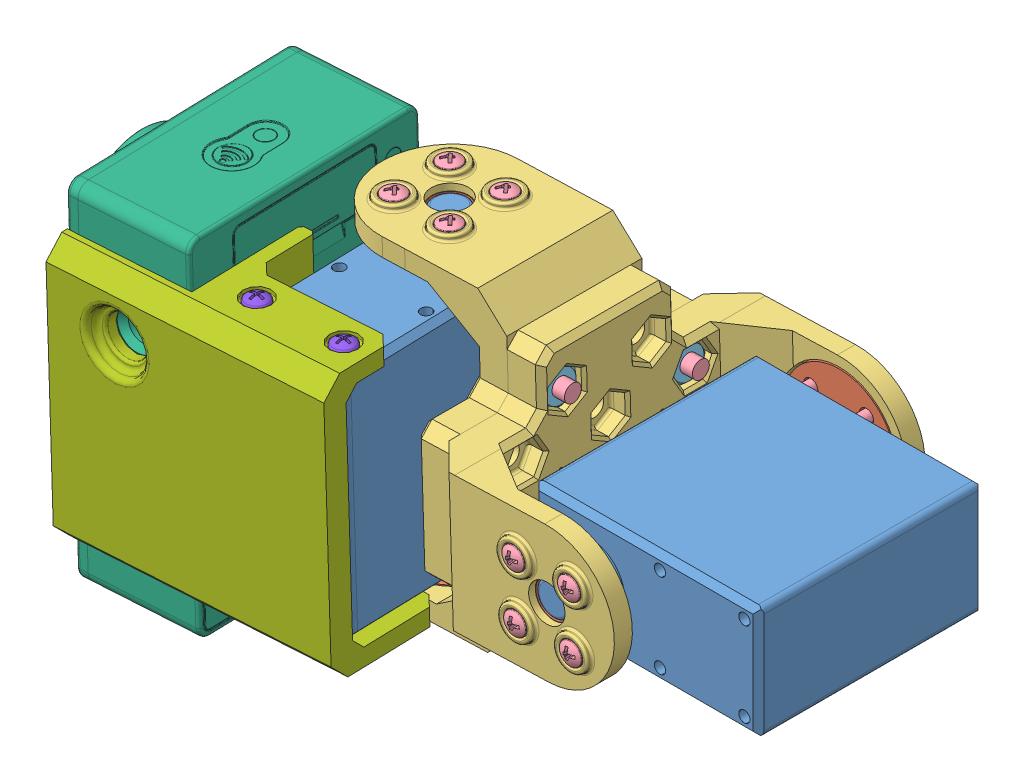
SolidWorks assembly Gimbal, configuration По умолчанию. Lengths in mm.
Overall size (118.51 61.53 66.21).
45 component instances, 8 part files, 20 mates.
Components (placement in the parent):
- Coxa-1: Coxa [По умолчанию] at origin size (86.89 58.77 58.33) (flexible)
  - Servo-1: Servo [По умолчанию] at origin size (40.32 20.63 52.9) (flexible)
    - RDS3115MG-1: RDS3115MG [00] at origin size (40 20 52)
    - Disk_25T-1: Disk_25T [Servo_Disk_T25] at (-10 0 44.4) x (0.032098 -0.999485 0) z (-0.999485 -0.032098 0) size (20 2 20)
    - Disk_25T-2: Disk_25T [Disk_T25] at (-10 0 -6.4) x (0.032098 -0.999485 0) z (-0.999485 -0.032098 0) size (20 4.5 20)
  - FemurPart4-3: FemurPart4 [По умолчанию] at (-10 0 -7.6) x (0.032098 -0.999485 0) z (0 0 1) size (45.2 34 57.2)
  - FemurPart4-4: FemurPart4 [По умолчанию] at (-54.8632 26.1734 19.9999) x (0 0 1) z (0.032098 -0.999485 0) size (45.2 34 57.2)
  - pan head cross recess screw_iso-1: pan head cross recess screw_iso [ISO 7045 - M2 x 5 - Z --- 5S] at (-59.8618 27.6137 15.0502) x (0.032098 -0.999485 0) z (-0.73565 -0.023625 0.67695) size (6.56 4 4)
  - pan head cross recess screw_iso-2: pan head cross recess screw_iso [ISO 7045 - M2 x 5 - Z --- 5S] at (-49.9674 27.9314 15.0502) x (0.032098 -0.999485 0) z (-0.73565 -0.023625 0.67695) size (6.56 4 4)
  - pan head cross recess screw_iso-3: pan head cross recess screw_iso [ISO 7045 - M2 x 5 - Z --- 5S] at (-59.8618 27.6137 24.9496) x (0.032098 -0.999485 0) z (-0.73565 -0.023625 0.67695) size (6.56 4 4)
  - pan head cross recess screw_iso-4: pan head cross recess screw_iso [ISO 7045 - M2 x 5 - Z --- 5S] at (-49.9674 27.9314 24.9496) x (0.032098 -0.999485 0) z (-0.73565 -0.023625 0.67695) size (6.56 4 4)
  - pan head cross recess screw_iso-5: pan head cross recess screw_iso [ISO 7045 - M2 x 5 - Z --- 5S] at (-48.0929 -30.4385 24.9496) x (-0.032098 0.999485 0) z (0.731511 0.023492 0.681425) size (6.56 4 4)
  - pan head cross recess screw_iso-6: pan head cross recess screw_iso [ISO 7045 - M2 x 5 - Z --- 5S] at (-57.9873 -30.7563 24.9496) x (-0.032098 0.999485 0) z (0 0 1) size (6.56 4 4)
  - pan head cross recess screw_iso-7: pan head cross recess screw_iso [ISO 7045 - M2 x 5 - Z --- 5S] at (-57.9873 -30.7563 15.0502) x (-0.032098 0.999485 0) z (0 0 1) size (6.56 4 4)
  - pan head cross recess screw_iso-8: pan head cross recess screw_iso [ISO 7045 - M2 x 5 - Z --- 5S] at (-48.0929 -30.4385 15.0502) x (-0.032098 0.999485 0) z (0 0 1) size (6.56 4 4)
  - pan head cross recess screw_iso-9: pan head cross recess screw_iso [ISO 7045 - M2 x 5 - Z --- 5S] at (-4.8939 -4.7883 49.2) x (0 0 -1) z (0.994673 0.103085 0) size (6.56 4 4)
  - pan head cross recess screw_iso-10: pan head cross recess screw_iso [ISO 7045 - M2 x 5 - Z --- 5S] at (-10 0 41.6) x (0 0 -1) z (0.994673 0.103085 0) size (6.56 4 4)
  - pan head cross recess screw_iso-11: pan head cross recess screw_iso [ISO 7045 - M2 x 5 - Z --- 5S] at (-10 0 43.6) x (0 0 -1) z (0.994673 0.103085 0) size (6.56 4 4)
  - pan head cross recess screw_iso-12: pan head cross recess screw_iso [ISO 7045 - M2 x 5 - Z --- 5S] at (-14.7883 -5.1061 49.2) x (0 0 -1) z (0.994673 0.103085 0) size (6.56 4 4)
  - pan head cross recess screw_iso-13: pan head cross recess screw_iso [ISO 7045 - M2 x 5 - Z --- 5S] at (-15.1061 4.7883 49.2) x (0 0 -1) z (0.994673 0.103085 0) size (6.56 4 4)
  - pan head cross recess screw_iso-14: pan head cross recess screw_iso [ISO 7045 - M2 x 5 - Z --- 5S] at (-5.2117 5.1061 49.2) x (0 0 -1) z (0.994673 0.103085 0) size (6.56 4 4)
  - pan head cross recess screw_iso-15: pan head cross recess screw_iso [ISO 7045 - M2 x 5 - Z --- 5S] at (-4.8939 -4.7883 -9.2) x (0 0 1) z (-0.958293 -0.285786 0) size (6.56 4 4)
  - pan head cross recess screw_iso-16: pan head cross recess screw_iso [ISO 7045 - M2 x 5 - Z --- 5S] at (-14.7883 -5.1061 -9.2) x (0 0 1) z (-0.958293 -0.285786 0) size (6.56 4 4)
  - pan head cross recess screw_iso-17: pan head cross recess screw_iso [ISO 7045 - M2 x 5 - Z --- 5S] at (-15.1061 4.7883 -9.2) x (0 0 1) z (-0.958293 -0.285786 0) size (6.56 4 4)
  - pan head cross recess screw_iso-18: pan head cross recess screw_iso [ISO 7045 - M2 x 5 - Z --- 5S] at (-5.2117 5.1061 -9.2) x (0 0 1) z (-0.958293 -0.285786 0) size (6.56 4 4)
  - pan head cross recess screw_iso-19: pan head cross recess screw_iso [ISO 7045 - M3 x 10 - Z --- 10N] at (-10 0 -8.8) x (0 0 1) z (-0.958293 -0.285786 0) size (12.35 5.6 5.6)
  - pan head cross recess screw_iso-20: pan head cross recess screw_iso [ISO 7045 - M3 x 10 - Z --- 10N] at (-37.6266 6.6165 4.9999) x (0.999485 0.032098 0) z (-0.021408 0.666616 -0.745094) size (12.35 5.6 5.6)
  - pan head cross recess screw_iso-21: pan head cross recess screw_iso [ISO 7045 - M3 x 10 - Z --- 10N] at (-37.1451 -8.3757 34.9999) x (0.999485 0.032098 0) z (0.022707 -0.707059 -0.706789) size (12.35 5.6 5.6)
  - pan head cross recess screw_iso-22: pan head cross recess screw_iso [ISO 7045 - M3 x 10 - Z --- 10N] at (-37.8674 14.1128 27.5) x (0.999485 0.032098 0) z (0.027077 -0.843132 -0.537024) size (12.35 5.6 5.6)
  - pan head cross recess screw_iso-23: pan head cross recess screw_iso [ISO 7045 - M3 x 10 - Z --- 10N] at (-36.9044 -15.8718 12.5) x (0.999485 0.032098 0) z (-0.03148 0.980231 0.195335) size (12.35 5.6 5.6)
  - nut-1: nut [00] at (-28.3314 6.9151 4.9999) x (0.032092 -0.999304 0.019008) z (-0.999485 -0.032098 0) size (5.5 6.35 1.8)
  - nut-2: nut [00] at (-28.5721 14.4113 27.5) x (0.028029 -0.872784 -0.487301) z (-0.999485 -0.032098 0) size (5.5 6.35 1.8)
  - nut-3: nut [00] at (-27.6092 -15.5732 12.5) x (0.026892 -0.837382 -0.545956) z (-0.999485 -0.032098 0) size (5.5 6.35 1.8)
  - nut-4: nut [00] at (-27.8499 -8.0772 34.9999) x (0.032 -0.996424 0.078198) z (-0.999485 -0.032098 0) size (5.5 6.35 1.8)
- Servo-1: Servo [По умолчанию] at (-53.0421 -21.3927 29.9956) x (0.029326 0.000942 0.999569) z (-0.032098 0.999485 0) size (40.29 20.58 52.9) (flexible)
  - RDS3115MG-1: RDS3115MG [00] at origin size (40 20 52)
  - Disk_25T-1: Disk_25T [Servo_Disk_T25] at (-10 0 44.4) x (-0.999569 0.029341 0) z (0.029341 0.999569 0) size (20 2 20)
  - Disk_25T-2: Disk_25T [Disk_T25] at (-10 0 -6.4) x (-0.999569 0.029341 0) z (0.029341 0.999569 0) size (20 4.5 20)
- Xiaomi_Yi-1: Xiaomi_Yi [По умолчанию] at (-68.4437 -1.877 31.3295) x (-0.032098 0.999485 0) z (-0.029326 -0.000942 -0.999569) size (60.6 28.52 42.21)
- CameraHolder-1: CameraHolder [По умолчанию] at (-36.7503 -23.871 84.4211) x (-0.999054 -0.032084 0.029341) z (-0.032098 0.999485 0) size (48 24 46)
- iso 7049 - st2,2x9,5-1: iso 7049 - st2,2x9,5 [00] at (-61.065 10.8664 47.7081) x (0.99897 0.032082 0.032098) z (-0.032098 0.999485 0) size (4 4 11.09)
- iso 7049 - st2,2x9,5-2: iso 7049 - st2,2x9,5 [00] at (-46.0792 11.3477 47.268) x (0.99897 0.032082 0.032098) z (-0.032098 0.999485 0) size (4 4 11.09)
- iso 7049 - st2,2x9,5-3: iso 7049 - st2,2x9,5 [00] at (-45.9962 -13.6626 39.7859) x (-0.85551 -0.027474 -0.517057) z (0.032098 -0.999485 0) size (4 4 11.09)
- iso 7049 - st2,2x9,5-4: iso 7049 - st2,2x9,5 [00] at (-59.983 -14.1117 40.1967) x (-0.85551 -0.027474 -0.517057) z (0.032098 -0.999485 0) size (4 4 11.09)
- iso 7049 - st2,2x9,5-5: iso 7049 - st2,2x9,5 [00] at (-52.7843 -13.8806 46.9883) x (-0.85551 -0.027474 -0.517057) z (0.032098 -0.999485 0) size (4 4 11.09)
Mates (geometry in assembly coordinates):
- Концентричный1: concentric anti-aligned: cylinder of Coxa-1/pan head cross recess screw_iso-7 through (-57.172 -56.1432 15.0502) axis (0.032098 -0.999485 0) radius 1; cylinder of Servo-1/Disk_25T-2 through (-58.1413 -25.9587 15.0502) axis (-0.032098 0.999485 0) radius 1.25
- Концентричный2: concentric anti-aligned: cylinder of Coxa-1/pan head cross recess screw_iso-5 through (-47.2776 -55.8254 24.9496) axis (0.032098 -0.999485 0) radius 1; cylinder of Servo-1/Disk_25T-2 through (-48.2469 -25.641 24.9496) axis (-0.032098 0.999485 0) radius 1.25
- Совпадение1: coincident anti-aligned: plane of Coxa-1/FemurPart4-4 through (-53.1299 -27.7988 19.9999) normal (-0.032098 0.999485 0); plane of Servo-1/Disk_25T-2 through (-53.1299 -27.7988 19.9999) normal (0.032098 -0.999485 0)
- Ширина1: width aligned: plane of Xiaomi_Yi-1 through (-68.7975 28.4273 52.4204) normal (-0.032098 0.999485 0); plane of Xiaomi_Yi-1 through (-68.0899 -32.1813 10.2385) normal (0.032098 -0.999485 0); plane of Servo-1/RDS3115MG-1 through (-54.326 18.5867 29.9956) normal (-0.032098 0.999485 0); plane of Servo-1/RDS3115MG-1 through (-53.0421 -21.3927 29.9956) normal (0.032098 -0.999485 0)
- Граничный угол1: limit planar angle = 1.538693 rad aligned: plane of Coxa-1/Servo-1/RDS3115MG-1 through (-20 10 0) normal (-1 0 0); plane of Servo-1/RDS3115MG-1 through (-54.326 18.5867 29.9956) normal (-0.032098 0.999485 0)
- Концентричный3: concentric aligned: cylinder of Servo-1/RDS3115MG-1 through (-61.3057 18.3625 47.7081) axis (0.032098 -0.999485 0) radius 1; cylinder of CameraHolder-1 through (-61.402 21.361 47.7081) axis (0.032098 -0.999485 0) radius 1
- Концентричный4: concentric aligned: cylinder of Servo-1/RDS3115MG-1 through (-46.3199 18.8438 47.268) axis (0.032098 -0.999485 0) radius 1; cylinder of CameraHolder-1 through (-46.4162 21.8423 47.268) axis (0.032098 -0.999485 0) radius 1
- Совпадение4: coincident anti-aligned: plane of Servo-1/RDS3115MG-1 through (-54.326 18.5867 29.9956) normal (-0.032098 0.999485 0); plane of CameraHolder-1 through (-38.1305 19.1068 84.4211) normal (0.032098 -0.999485 0)
- Совпадение7: coincident anti-aligned: plane of Xiaomi_Yi-1 through (-66.8523 -32.1415 52.4204) normal (0.029326 0.000942 0.999569); plane of CameraHolder-1 through (-41.6922 18.9924 51.634) normal (-0.029326 -0.000942 -0.999569)
- Совпадение8: coincident aligned: plane of Xiaomi_Yi-1 through (-89.6236 -2.5572 31.9515) normal (-0.999054 -0.032084 0.029341); plane of CameraHolder-1 through (-87.3024 -25.4945 85.9057) normal (-0.999054 -0.032084 0.029341)
- Концентричный5: concentric aligned: cylinder of CameraHolder-1 through (-61.402 21.361 47.7081) axis (0.032098 -0.999485 0) radius 1; cylinder of iso 7049 - st2,2x9,5-1 through (-61.065 10.8664 47.7081) axis (0.032098 -0.999485 0) radius 0.815
- Совпадение9: coincident aligned: plane of iso 7049 - st2,2x9,5-1 through (-62.1841 20.3354 47.682) normal (0.032098 -0.999485 0); plane of iso 7049 - st2,2x9,5-2 through (-47.1983 20.8166 47.2418) normal (0.032098 -0.999485 0)
- Концентричный6: concentric aligned: cylinder of CameraHolder-1 through (-46.4162 21.8423 47.268) axis (0.032098 -0.999485 0) radius 1; cylinder of iso 7049 - st2,2x9,5-2 through (-46.0792 11.3477 47.268) axis (0.032098 -0.999485 0) radius 0.815
- Совпадение10: coincident anti-aligned: plane of CameraHolder-1 through (-46.3841 20.8428 47.268) normal (-0.032098 0.999485 0); plane of iso 7049 - st2,2x9,5-2 through (-47.1983 20.8166 47.2418) normal (0.032098 -0.999485 0)
- Концентричный7: concentric anti-aligned: cylinder of CameraHolder-1 through (-45.7555 -21.1587 39.7859) axis (0.032098 -0.999485 0) radius 1; cylinder of iso 7049 - st2,2x9,5-3 through (-45.9962 -13.6626 39.7859) axis (-0.032098 0.999485 0) radius 0.815
- Совпадение11: coincident aligned: plane of iso 7049 - st2,2x9,5-3 through (-44.994 -23.1353 40.2073) normal (-0.032098 0.999485 0); plane of iso 7049 - st2,2x9,5-4 through (-58.9808 -23.5844 40.6181) normal (-0.032098 0.999485 0)
- Совпадение12: coincident aligned: plane of iso 7049 - st2,2x9,5-3 through (-44.994 -23.1353 40.2073) normal (-0.032098 0.999485 0); plane of iso 7049 - st2,2x9,5-5 through (-51.7821 -23.3533 47.4097) normal (-0.032098 0.999485 0)
- Концентричный8: concentric anti-aligned: cylinder of CameraHolder-1 through (-59.7422 -21.6079 40.1967) axis (0.032098 -0.999485 0) radius 1; cylinder of iso 7049 - st2,2x9,5-4 through (-59.983 -14.1117 40.1967) axis (-0.032098 0.999485 0) radius 0.815
- Концентричный9: concentric anti-aligned: cylinder of CameraHolder-1 through (-52.5436 -21.3767 46.9883) axis (0.032098 -0.999485 0) radius 1; cylinder of iso 7049 - st2,2x9,5-5 through (-52.7843 -13.8806 46.9883) axis (-0.032098 0.999485 0) radius 0.815
- Совпадение13: coincident anti-aligned: plane of CameraHolder-1 through (-45.6913 -23.1577 39.7859) normal (0.032098 -0.999485 0); plane of iso 7049 - st2,2x9,5-3 through (-44.994 -23.1353 40.2073) normal (-0.032098 0.999485 0)
